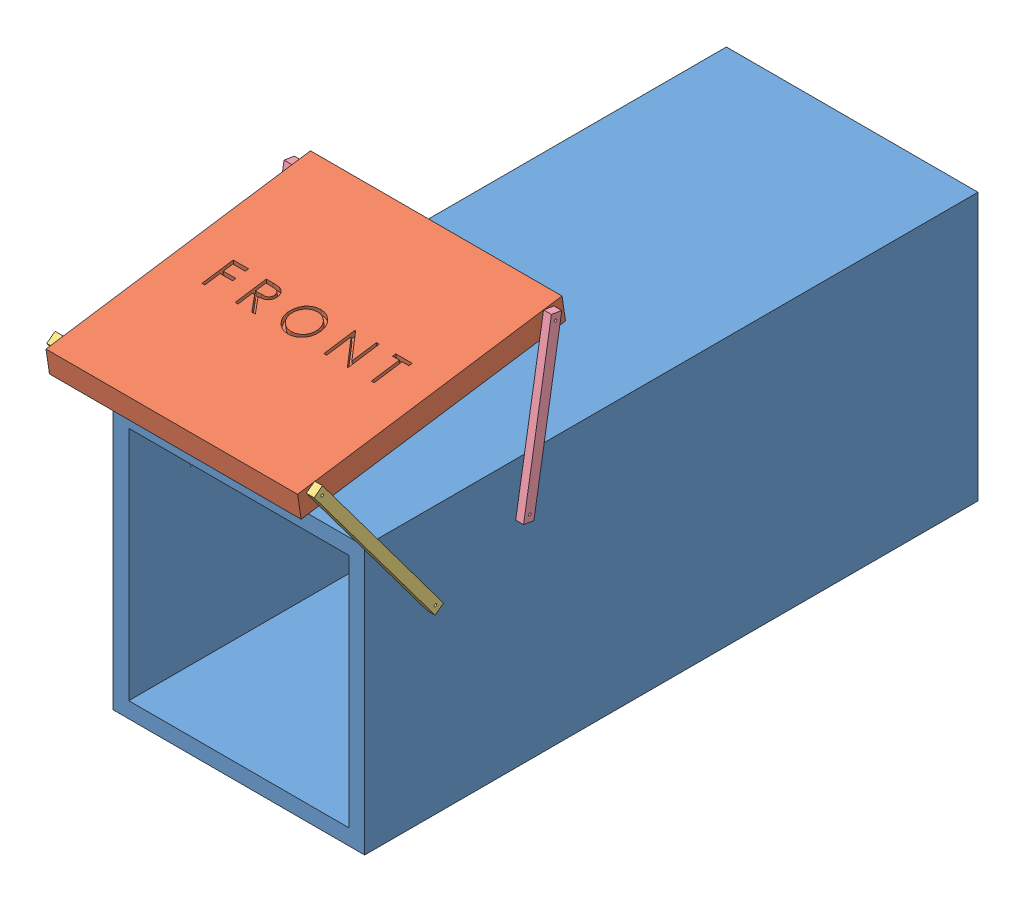
SolidWorks assembly Assem1, configuration Default. Lengths in mm.
Overall size (2590.8 3735.09 6593.25).
6 component instances, 4 part files, 8 mates.
Components (placement in the parent):
- container-1: container [Default] at (2575.7708 3022.9444 4503.4427) size (2438.4 2590.8 5943.6)
- door_v2-2: door_v2 [Default] at (2577.7177 5158.1242 6750.6272) x (1 0 0) z (0 0.989017 0.147804) size (2438.4 2590.8 228.6)
- LowBar_v3-1: LowBar_v3 [Default] at (3833.0708 4291.6049 7338.0736) x (0 -0.598035 0.80147) z (-1 0 0) size (101.6 1961.78 76.2)
- TopBar_v3-1: TopBar_v3 [Default] at (3833.0708 4612.9452 5750.4276) x (0 -0.163524 -0.986539) z (1 0 0) size (101.6 1651.12 76.2)
- LowBar_v3-2: LowBar_v3 [Default] at (1318.4708 4291.6049 7338.0736) x (0 -0.598035 0.80147) z (-1 0 0) size (101.6 1961.78 76.2)
- TopBar_v3-2: TopBar_v3 [Default] at (1318.4708 4612.9452 5750.4276) x (0 -0.163524 -0.986539) z (1 0 0) size (101.6 1651.12 76.2)
Mates (geometry in assembly coordinates):
- Hinge1: hinge: circle of LowBar_v3-1; circle of container-1; plane of LowBar_v3-1 through (3794.9708 4291.6049 7338.0736) normal (-1 0 0); plane of container-1 through (3794.9708 1727.5444 7551.4427) normal (1 0 0)
- Hinge2: hinge: circle of container-1; circle of TopBar_v3-1; plane of container-1 through (3794.9708 1727.5444 7551.4427) normal (1 0 0); plane of TopBar_v3-1 through (3794.9708 4612.9452 5750.4276) normal (-1 0 0)
- Hinge3: hinge: circle of LowBar_v3-2; circle of container-1; plane of LowBar_v3-2 through (1356.5708 4291.6049 7338.0736) normal (1 0 0); plane of container-1 through (1356.5708 1727.5444 7551.4427) normal (-1 0 0)
- Hinge4: hinge: circle of TopBar_v3-2; circle of container-1; plane of TopBar_v3-2 through (1356.5708 4612.9452 5750.4276) normal (1 0 0); plane of container-1 through (1356.5708 1727.5444 7551.4427) normal (-1 0 0)
- Hinge5: hinge: circle of LowBar_v3-2; circle of door_v2-2; plane of door_v2-2 through (1356.5708 5158.1242 6750.6272) normal (-1 0 0); plane of LowBar_v3-2 through (1356.5708 4291.6049 7338.0736) normal (1 0 0)
- Hinge6: hinge: circle of TopBar_v3-2; circle of door_v2-2; plane of door_v2-2 through (1356.5708 5158.1242 6750.6272) normal (-1 0 0); plane of TopBar_v3-2 through (1356.5708 4612.9452 5750.4276) normal (1 0 0)
- Hinge7: hinge: circle of TopBar_v3-1; circle of door_v2-2; plane of door_v2-2 through (3794.9708 5158.1242 6750.6272) normal (1 0 0); plane of TopBar_v3-1 through (3794.9708 4612.9452 5750.4276) normal (-1 0 0)
- Hinge8: hinge: circle of LowBar_v3-1; circle of door_v2-2; plane of door_v2-2 through (3794.9708 5158.1242 6750.6272) normal (1 0 0); plane of LowBar_v3-1 through (3794.9708 4291.6049 7338.0736) normal (-1 0 0)
